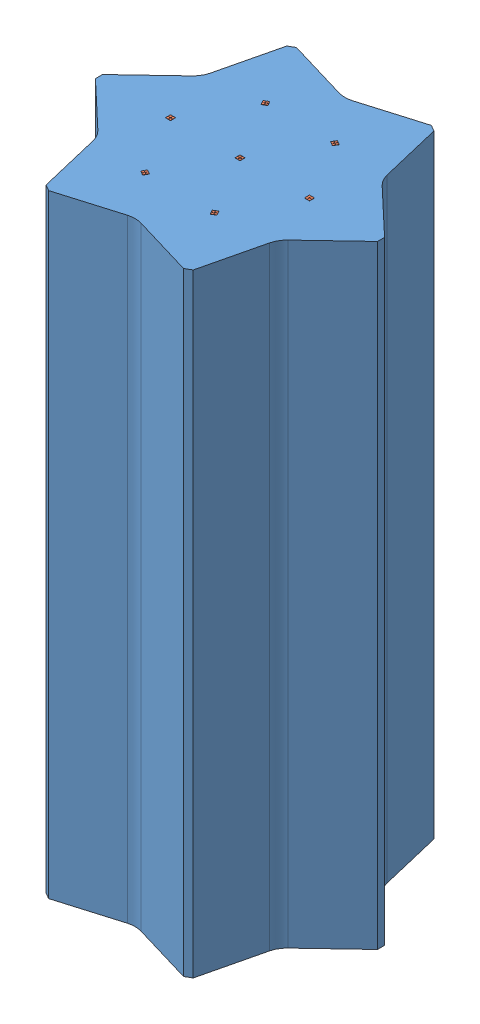
SolidWorks assembly SArUnit, configuration 默认. Lengths in mm.
Overall size (690 1500.5 606.22).
8 component instances, 2 part files, 6 mates.
Components (placement in the parent):
- SArContainer-1: SArContainer [默认] at origin size (690 1500 606.22)
- SiPMArray-Ar-2: SiPMArray-Ar [默认] at (0 1500 0) size (12 0.5 12)
- SiPMArray-Ar-3: SiPMArray-Ar [默认] at (-170 1500 0) size (12 0.5 12)
- SiPMArray-Ar-4: SiPMArray-Ar [默认] at (-85 1500 147.2243) x (0.5 0 -0.866025) z (0.866025 0 0.5) size (12 0.5 12)
- SiPMArray-Ar-5: SiPMArray-Ar [默认] at (85 1500 147.2243) x (-0.5 0 -0.866025) z (0.866025 0 -0.5) size (12 0.5 12)
- SiPMArray-Ar-6: SiPMArray-Ar [默认] at (170 1500 0) x (-1 0 0) z (0 0 -1) size (12 0.5 12)
- SiPMArray-Ar-7: SiPMArray-Ar [默认] at (85 1500 -147.2243) x (-0.5 0 0.866025) z (-0.866025 0 -0.5) size (12 0.5 12)
- SiPMArray-Ar-8: SiPMArray-Ar [默认] at (-85 1500 -147.2243) x (0.5 0 0.866025) z (-0.866025 0 0.5) size (12 0.5 12)
Mates (geometry in assembly coordinates):
- 重合1: coincident: point of SArContainer-1; point of SiPMArray-Ar-2
- 平行1: parallel anti-aligned: line of SiPMArray-Ar-2 through (-6 1500.5 6) axis (1 0 0)
- 平行2: parallel anti-aligned: line of SArContainer-1 through (1500 0 0) axis (0 0 1); line of SiPMArray-Ar-2 through (6 1500.5 0.2) axis (0 -1 0)
- 重合5: coincident: point of SiPMArray-Ar-3; point of assembly
- 平行3: parallel anti-aligned: line of SiPMArray-Ar-3 through (-169.8 1500.5 -0.2) axis (1 0 0)
- 平行4: parallel anti-aligned: line of SArContainer-1 through (1500 0 0) axis (0 0 1); line of SiPMArray-Ar-3 through (-164 1500.5 0.2) axis (0 -1 0)
